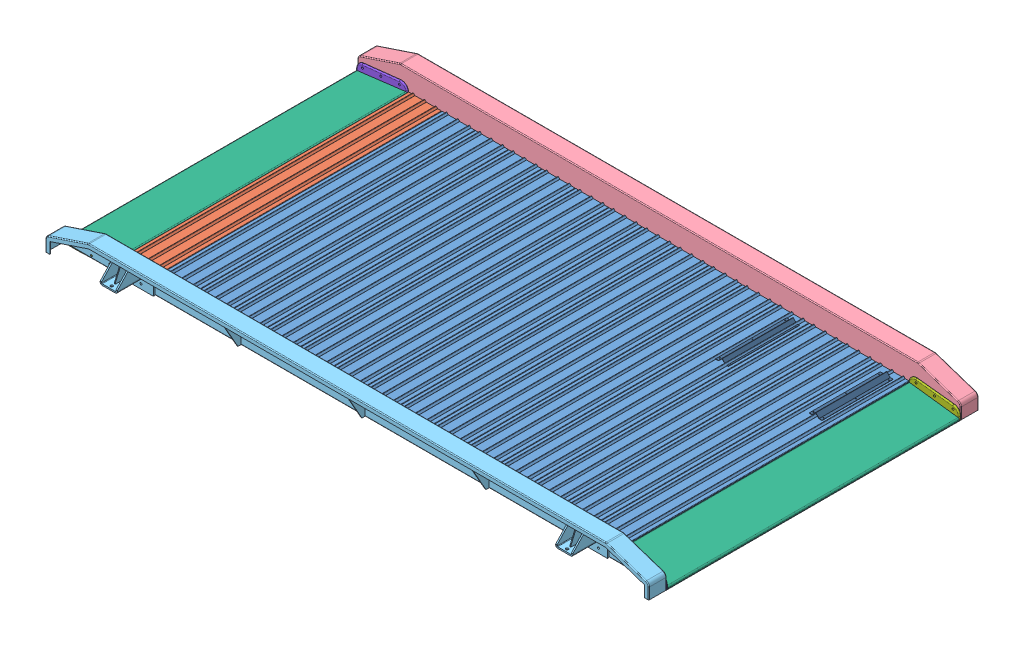
SolidWorks assembly 上载车板主体结构, configuration 默认. Lengths in mm.
Overall size (4245 204.29 2470).
37 component instances, 10 part files, 23 mates.
Components (placement in the parent):
- 波纹板-15: 波纹板 [默认] at (-117.9263 -16.7588 1023) size (272.3 65.93 2066)
- 波纹板-16: 波纹板 [默认] at (-352.9263 -16.7588 1023) size (272.3 65.93 2066)
- 波纹板-17: 波纹板 [默认] at (-587.9263 -16.7588 1023) size (272.3 65.93 2066)
- 波纹板-18: 波纹板 [默认] at (-822.9263 -16.7588 1023) size (272.3 65.93 2066)
- 波纹板-19: 波纹板 [默认] at (-1057.9263 -16.7588 1023) size (272.3 65.93 2066)
- 波纹板-20: 波纹板 [默认] at (-1292.9263 -16.7588 1023) size (272.3 65.93 2066)
- 波纹板-21: 波纹板 [默认] at (-1527.9263 -16.7588 1023) size (272.3 65.93 2066)
- 波纹板-22: 波纹板 [默认] at (-1762.9263 -16.7588 1023) size (272.3 65.93 2066)
- 波纹板-23: 波纹板 [默认] at (-1997.9263 -16.7588 1023) size (272.3 65.93 2066)
- 波纹板-24: 波纹板 [默认] at (-2232.9263 -16.7588 1023) size (272.3 65.93 2066)
- 波纹板-25: 波纹板 [默认] at (-2467.9263 -16.7588 1023) size (272.3 65.93 2066)
- 波纹板-26: 波纹板 [默认] at (-2702.9263 -16.7588 1023) size (272.3 65.93 2066)
- 波纹板-27: 波纹板 [默认] at (-2937.9263 -16.7588 1023) size (272.3 65.93 2066)
- 波纹板二-14: 波纹板二 [默认] at (-3407.9263 -19.0588 1023) size (235 65.93 2066)
- 车板加强横梁-1: 车板加强横梁 [默认<按加工>] at (-35.9263 8.9412 2056) size (150 50 2070)
- 上车板边梁折弯件2-1: 上车板边梁折弯件2 [默认] at (-1645.4263 -23.0588 1021) size (4245 200.11 245)
- 上车板边梁折弯件1-1: 上车板边梁折弯件1 [默认] at (-1645.4263 -23.0588 3091) size (4245 200.11 245)
- 斜坡板焊接-3: 斜坡板焊接 [默认] at (-2974.4731 -1592.6091 6) size (360 109.38 2070)
  - 斜坡板折弯（花纹钢板）-1: 斜坡板折弯（花纹钢板） [默认] at (-433.4532 1575.2553 1025) size (360 63.67 2050)
  - 斜坡板安装板-1: 斜坡板安装板 [默认] at origin size (360 108.63 10)
  - 斜坡板安装板2-1: 斜坡板安装板2 [默认] at (0 0 -2040) size (360 109.25 10)
  - 零件13^斜坡板焊接-1: 零件13^斜坡板焊接 [默认] at origin size (352 56.27 6) (virtual)
  - 零件13^斜坡板焊接-2: 零件13^斜坡板焊接 [默认] at (0 0 -200) size (352 56.27 6) (virtual)
  - 零件13^斜坡板焊接-3: 零件13^斜坡板焊接 [默认] at (0 0 -1600) size (352 56.27 6) (virtual)
  - 零件13^斜坡板焊接-4: 零件13^斜坡板焊接 [默认] at (0 0 -1400) size (352 56.27 6) (virtual)
- 斜坡板焊接-4: 斜坡板焊接 [默认] at (-316.3794 -1592.6091 4106) x (-1 0 0) z (0 0 -1) size (360 109.38 2070)
  - 斜坡板折弯（花纹钢板）-1: 斜坡板折弯（花纹钢板） [默认] at (-433.4532 1575.2553 1025) size (360 63.67 2050)
  - 斜坡板安装板-1: 斜坡板安装板 [默认] at origin size (360 108.63 10)
  - 斜坡板安装板2-1: 斜坡板安装板2 [默认] at (0 0 -2040) size (360 109.25 10)
  - 零件13^斜坡板焊接-1: 零件13^斜坡板焊接 [默认] at origin size (352 56.27 6) (virtual)
  - 零件13^斜坡板焊接-2: 零件13^斜坡板焊接 [默认] at (0 0 -200) size (352 56.27 6) (virtual)
  - 零件13^斜坡板焊接-3: 零件13^斜坡板焊接 [默认] at (0 0 -1600) size (352 56.27 6) (virtual)
  - 零件13^斜坡板焊接-4: 零件13^斜坡板焊接 [默认] at (0 0 -1400) size (352 56.27 6) (virtual)
- 车板加强横梁-2: 车板加强横梁 [默认<按加工>] at (-3254.9263 8.9412 2056) size (150 50 2070)
- 阻车器-1: 阻车器 [Default] at (-697.6563 38.2412 1071) size (90 26.09 500)
- 阻车器-2: 阻车器 [Default] at (-38.974 38.2412 1071) size (90 26.09 500)
- 波纹板-29: 波纹板 [默认] at (-3172.9263 -16.7588 1023) size (272.3 65.93 2066)
Mates (geometry in assembly coordinates):
- 重合15: coincident: plane of 波纹板-16 through (-306.4263 33.9412 3089) normal (0 -1 0); plane of 车板加强横梁-1 through (-35.9263 33.9412 1031) normal (0 1 0)
- 相切3: tangent: plane of 波纹板二-14 through (-3384.4263 -19.0598 1033.5) normal (-1 0 0); cylinder of 上车板边梁折弯件2-1 through (-3389.9263 -23.1727 1038) axis (0 1 0) radius 5.5
- 距离5: distance = 2 mm: plane of 上车板边梁折弯件2-1 through (-1645.4263 -23.0588 1021) normal (0 0 1); plane of 波纹板二-14 through (-3361.0121 33.9412 1023) normal (0 0 -1)
- 距离4: distance = 2 mm: plane of 上车板边梁折弯件1-1 through (-1645.4263 -23.0588 3091) normal (0 0 -1); plane of 波纹板-17 through (-585.6263 32.9412 3089) normal (0 0 1)
- 相切4: tangent: plane of 波纹板二-14 through (-3395.4263 -19.0598 3078.5) normal (1 0 0); cylinder of 上车板边梁折弯件1-1 through (-3389.9263 -23.1727 3074) axis (0 1 0) radius 5.5
- 同心3: concentric: cylinder of 车板加强横梁-1 through (14.0737 8.9412 3081) axis (0 0 1) radius 7; cylinder of 上车板边梁折弯件1-1 through (14.0737 8.9412 3216.001) axis (0 0 -1) radius 7
- 重合23: coincident: plane of 波纹板二-14 through (-3407.9263 -19.0588 3089) normal (-1 0 0); plane of 斜坡板焊接-3/斜坡板折弯（花纹钢板）-1 through (-3407.9263 -17.3538 3081) normal (1 0 0)
- 重合24: coincident: plane of 上车板边梁折弯件1-1 through (-1645.4263 -23.0588 3091) normal (0 0 -1); plane of 斜坡板焊接-3/斜坡板安装板-1 through (-3457.9263 31.3962 3091) normal (0 0 1)
- 重合27: coincident: plane of 波纹板二-14 through (-3407.9263 36.2412 3089) normal (0 1 0); line of 斜坡板焊接-3/斜坡板折弯（花纹钢板）-1 through (-3419.1666 36.2412 3081) axis (0 0 -1)
- 重合28: coincident: plane of 波纹板-15 through (117.0737 36.2412 3089) normal (1 0 0); plane of 斜坡板焊接-4/斜坡板折弯（花纹钢板）-1 through (117.0737 -17.3538 1031) normal (-1 0 0)
- 重合29: coincident: plane of 上车板边梁折弯件1-1 through (-1645.4263 -23.0588 3091) normal (0 0 -1); plane of 斜坡板焊接-4/斜坡板安装板2-1 through (167.0737 32.0212 3091) normal (0 0 1)
- 重合30: coincident: plane of 波纹板-15 through (88.5737 36.2412 3089) normal (0 1 0); line of 斜坡板焊接-4/斜坡板折弯（花纹钢板）-1 through (128.3141 36.2412 1031) axis (0 0 1)
- 同心4: concentric: cylinder of 上车板边梁折弯件1-1 through (-3304.9263 8.9412 3216.001) axis (0 0 -1) radius 7; cylinder of 车板加强横梁-2 through (-3304.9263 8.9412 3081) axis (0 0 1) radius 7
- 重合31: coincident: plane of 上车板边梁折弯件1-1 through (-1645.4263 -23.0588 3091) normal (0 0 -1); plane of 车板加强横梁-2 through (-3204.9263 8.9412 3091) normal (0 0 1)
- 距离6: distance = 2 mm: plane of 波纹板二-14 through (-3404.6263 -16.7588 3089) normal (0 0 1); plane of 上车板边梁折弯件1-1 through (-1645.4263 -23.0588 3091) normal (0 0 -1)
- 重合36: coincident: plane of 车板加强横梁-1 through (14.0737 8.9412 1021) normal (0 0 -1); plane of 上车板边梁折弯件2-1 through (-1645.4263 -23.0588 1021) normal (0 0 1)
- 重合37: coincident: plane of 波纹板-26 through (-2656.4263 36.2412 3089) normal (0 1 0); plane of 阻车器-1 through (-627.5735 36.2412 1571) normal (0 -1 0)
- 距离9: distance = 50 mm: plane of 上车板边梁折弯件2-1 through (-1645.4263 -23.0588 1021) normal (0 0 1); plane of 阻车器-2 through (-19.0568 38.4412 1071) normal (0 0 -1)
- 重合40: coincident: plane of 波纹板二-14 through (-3172.9263 36.2412 3089) normal (1 0 0); plane of 波纹板-29 through (-3172.9263 -16.7588 3089) normal (-1 0 0)
- 重合41: coincident: plane of 波纹板二-14 through (-3172.9263 -16.7588 3089) normal (0 -1 0); plane of 波纹板-29 through (-3172.9263 -16.7588 3089) normal (0 1 0)
- 重合42: coincident: plane of 上车板边梁折弯件2-1 through (-3432.9263 -19.0588 1066) normal (0 1 0); plane of 波纹板-29 through (-3172.9263 -19.0588 3089) normal (0 -1 0)
- 重合43: coincident: plane of 波纹板-15 through (8.5737 36.2412 3089) normal (0 1 0); plane of 阻车器-2 through (31.1089 36.2412 1571) normal (0 -1 0)
- 距离10: distance = 50 mm: plane of 阻车器-1 through (-677.7391 38.4412 1071) normal (0 0 -1); plane of 上车板边梁折弯件2-1 through (-1645.4263 -23.0588 1021) normal (0 0 1)
